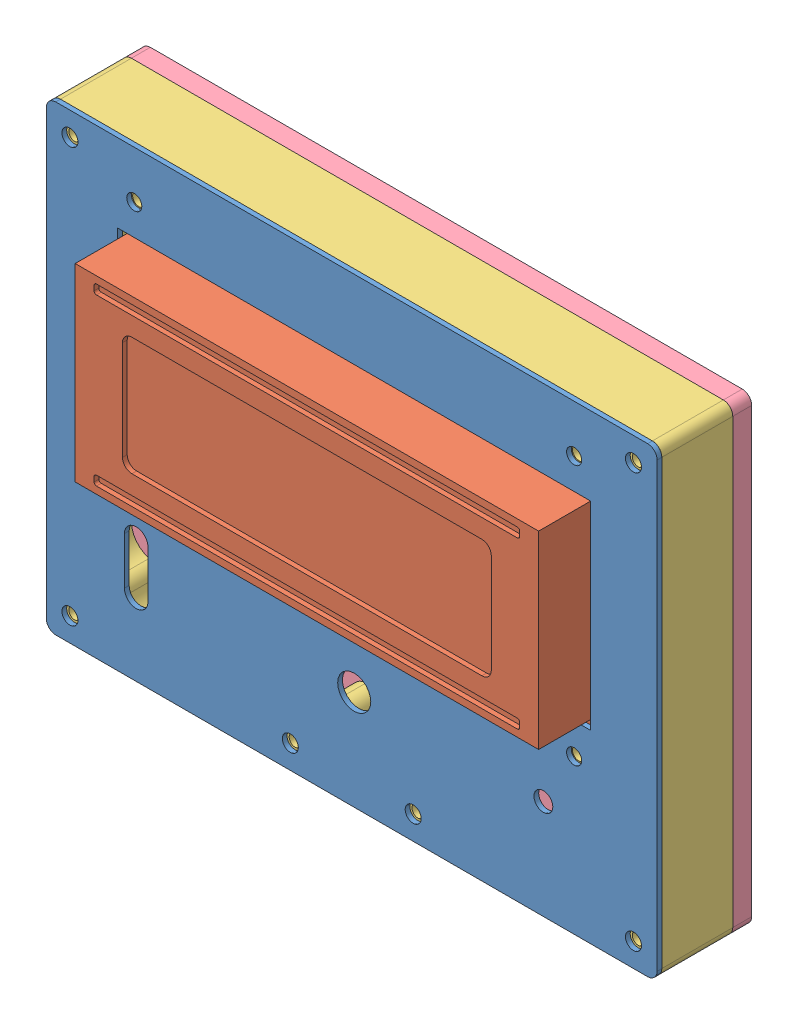
SolidWorks assembly New Panel Box, configuration Default. Lengths in mm.
Overall size (129.16 97.82 44.86).
4 component instances, 4 part files, 10 mates.
Components (placement in the parent):
- P0ANEL-1: P0ANEL [Default] at (8.066 80.2445 111.6053) size (129.16 97.62 1)
- lcd-1: lcd [Default] at (-30.4799 57.8649 102.6053) x (1 0 0) z (0 -1 0) size (98 15 60)
- panel case printed2-1: panel case printed2 [Default] at (0 0.4 120.6053) x (-1 0 0) z (0 0 -1) size (129.16 97.82 33.86)
- back cover-1: back cover [Default] at (0 0 96.6053) x (-1 0 0) z (0 0 -1) size (129.16 97.62 4)
Mates (geometry in assembly coordinates):
- Coincident1: coincident: plane of P0ANEL-1 through (118.5774 33.7875 111.6053) normal (0 0 -1); plane of lcd-1 through (105.5201 61.8649 109.6053) normal (0 0 1)
- Concentric1: concentric: cylinder of P0ANEL-1 through (10.0201 119.3649 112.6053) axis (0 0 -1) radius 1.6001; cylinder of lcd-1 through (10.0201 119.3649 109.6053) axis (0 0 -1) radius 1.75
- Parallel4: parallel: plane of P0ANEL-1 through (-6.5856 31.7875 112.6053) normal (0 -1 0); plane of lcd-1 through (105.5201 61.8649 109.6053) normal (0 -1 0)
- Concentric8: concentric: cylinder of lcd-1 through (10.0201 64.3649 109.6053) axis (0 0 -1) radius 1.75; cylinder of panel case printed2-1 through (10.0201 64.3649 143.2952) axis (0 0 -1) radius 1.35
- Concentric9: concentric: cylinder of lcd-1 through (103.0201 64.3649 109.6053) axis (0 0 -1) radius 1.75; cylinder of panel case printed2-1 through (103.0201 64.3649 143.2952) axis (0 0 -1) radius 1.35
- Coincident5: coincident: plane of P0ANEL-1 through (118.5774 33.7875 111.6053) normal (0 0 -1); plane of panel case printed2-1 through (120.5774 129.4077 111.6053) normal (0 0 1)
- Coincident22: coincident: plane of panel case printed2-1 through (-6.5856 129.4077 96.6053) normal (0 1 0); plane of back cover-1 through (-6.5856 129.4077 92.6053) normal (0 1 0)
- Coincident23: coincident: plane of panel case printed2-1 through (120.5774 127.4077 96.6053) normal (1 0 0); plane of back cover-1 through (120.5774 127.4077 92.6053) normal (1 0 0)
- Coincident26: coincident: plane of panel case printed2-1 through (-6.5856 127.4077 96.6053) normal (0 0 -1); plane of back cover-1 through (-6.5856 33.7875 96.6053) normal (0 0 1)
- Coincident27: coincident: plane of lcd-1 through (105.5201 61.8649 109.6053) normal (0 0 1); plane of panel case printed2-1 through (10.0201 64.3649 109.6053) normal (0 0 -1)
